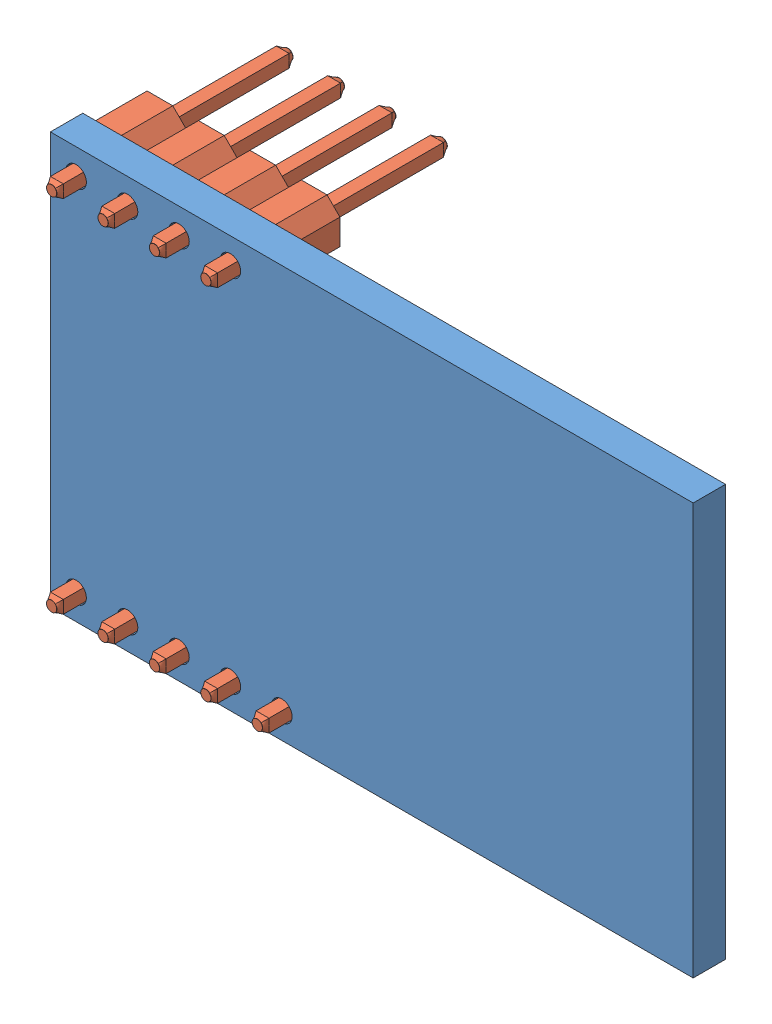
SolidWorks assembly SparkFun Venus GPS Logger with SMA Connector GPS-10920, configuration Default. Lengths in mm.
Overall size (31.75 20.32 11.76).
12 component instances, 2 part files, 6 mates.
Components (placement in the parent):
- venus_gps_flashv11sma-1: venus_gps_flashv11sma [Default] at origin size (31.75 20.32 1.6)
- Male Header 4 Pin-1: Male Header 4 Pin [Default] at (23.6544 78.7463 -24.1887) x (0 1 0) z (0 0 1) size (2.54 10.16 11.76)
  - Male Header Pin-1: Male Header Pin [Default] at (-59.6963 14.7644 21.6487) size (2.54 2.54 11.76)
  - Male Header Pin-2: Male Header Pin [Default] at (-59.6963 17.3044 21.6487) size (2.54 2.54 11.76)
  - Male Header Pin-3: Male Header Pin [Default] at (-59.6963 19.8444 21.6487) size (2.54 2.54 11.76)
  - Male Header Pin-4: Male Header Pin [Default] at (-59.6963 22.3844 21.6487) size (2.54 2.54 11.76)
- Male Header 5 Pin-1: Male Header 5 Pin [Default] at (11.7887 4.4863 -3.9935) x (0 1 0) z (0 0 1) size (2.54 12.7 11.76)
  - Male Header Pin-1: Male Header Pin [Default] at (-3.2163 0.3587 1.4535) size (2.54 2.54 11.76)
  - Male Header Pin-2: Male Header Pin [Default] at (-3.2163 2.8987 1.4535) size (2.54 2.54 11.76)
  - Male Header Pin-3: Male Header Pin [Default] at (-3.2163 5.4387 1.4535) size (2.54 2.54 11.76)
  - Male Header Pin-4: Male Header Pin [Default] at (-3.2163 7.9787 1.4535) size (2.54 2.54 11.76)
  - Male Header Pin-5: Male Header Pin [Default] at (-3.2163 10.5187 1.4535) size (2.54 2.54 11.76)
Mates (geometry in assembly coordinates):
- Coincident1: coincident anti-aligned: plane of venus_gps_flashv11sma-1 through (0 0 0) normal (0 0 -1); plane of Male Header 4 Pin-1/Male Header Pin-4 through (0 20.32 0) normal (0 0 1)
- Coincident6: coincident aligned: plane of venus_gps_flashv11sma-1 through (0 20.32 1.6) normal (-1 0 0); plane of Male Header 4 Pin-1/Male Header Pin-4 through (0 18.415 0) normal (-1 0 0)
- Coincident5: coincident aligned: plane of Male Header 4 Pin-1/Male Header Pin-4 through (1.905 20.32 0) normal (0 1 0); plane of venus_gps_flashv11sma-1 through (31.75 20.32 1.6) normal (0 1 0)
- Coincident7: coincident anti-aligned: plane of venus_gps_flashv11sma-1 through (0 0 0) normal (0 0 -1); plane of Male Header 5 Pin-1/Male Header Pin-5 through (0 2.54 0) normal (0 0 1)
- Coincident8: coincident aligned: plane of venus_gps_flashv11sma-1 through (0 20.32 1.6) normal (-1 0 0); plane of Male Header 5 Pin-1/Male Header Pin-5 through (0 0.635 0) normal (-1 0 0)
- Coincident9: coincident aligned: plane of venus_gps_flashv11sma-1 through (0 0 1.6) normal (0 -1 0); plane of Male Header 5 Pin-1/Male Header Pin-5 through (1.905 0 0) normal (0 -1 0)
